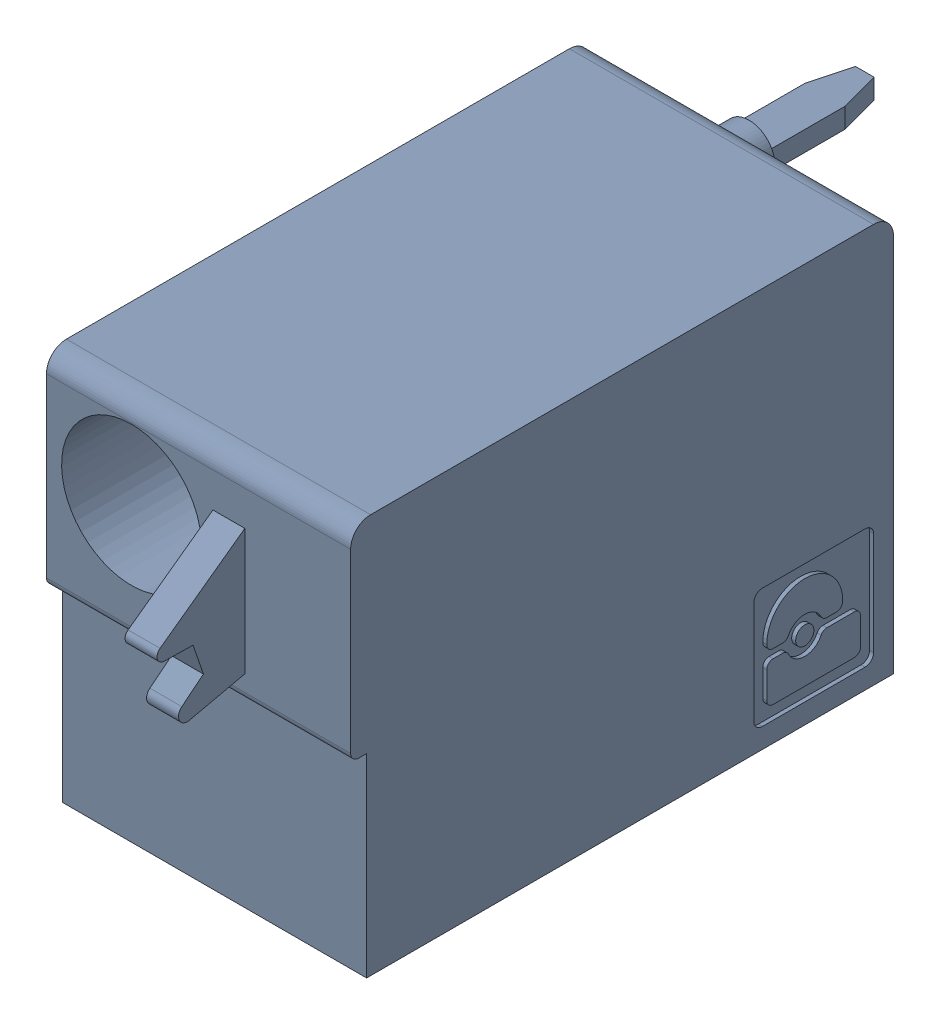
SolidWorks assembly J31, configuration Default. Lengths in mm.
Overall size (7.62 10 19.2).
2 component instances, 1 part files, 0 mates.
Components (placement in the parent):
- 1790487-1: 1790487 [Default] at (76.605 -15.67 -10.6) x (0 1 0) z (1 0 0) size (10 19.2 7.62)
  - ffkdsa1-v2-7.62-1: ffkdsa1-v2-7.62 [Default] at (-15.6914 -27.508 9.12) x (0 -1 0) z (0 0 1) size (19.2 10 7.62)
